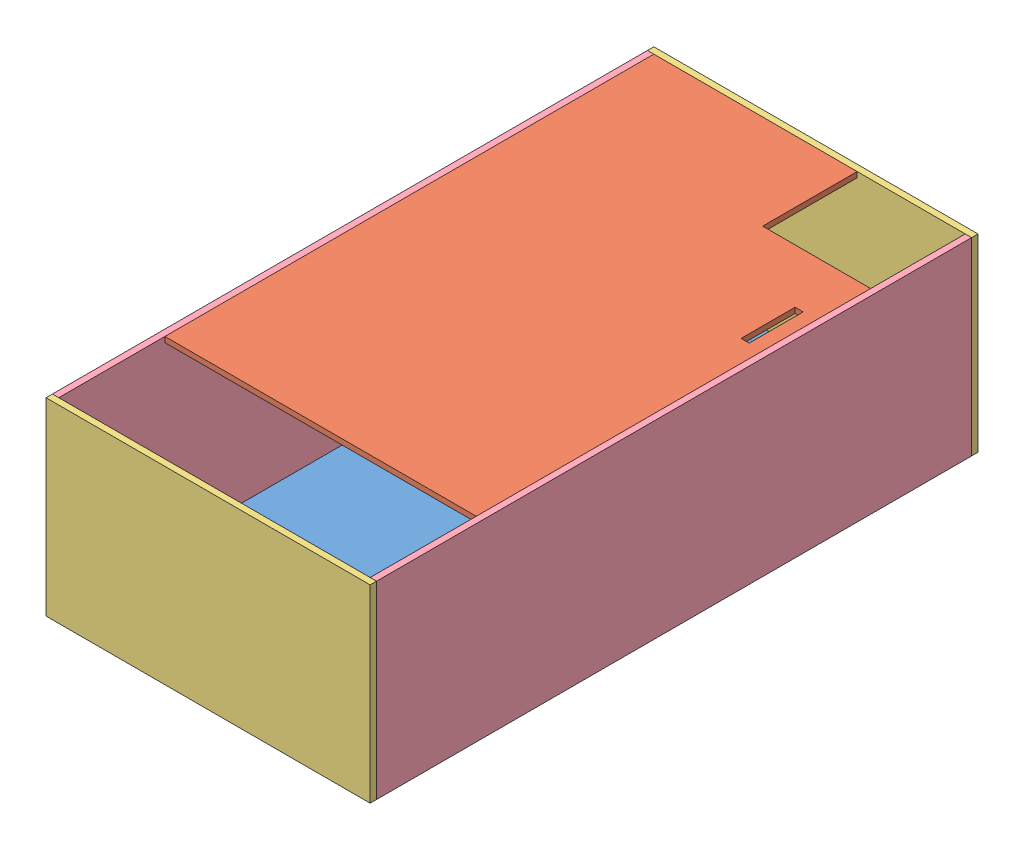
SolidWorks assembly pumpresovoir, configuration Default. Lengths in mm.
Overall size (152.4 88.9 285.75).
6 component instances, 4 part files, 13 mates.
Components (placement in the parent):
- waterbottom2-1: waterbottom2 [Default] at (-99.0826 -3.5009 -125.4041) size (146.41 3 279.76)
- top-1: top [Default] at (47.323 82.8591 -125.4041) x (0 0 1) z (-1 0 0) size (229.87 2.54 146.41)
- frontandback-1: frontandback [Default] at (-102.0798 85.3991 -128.4013) size (152.4 88.9 3)
- frontandback-2: frontandback [Default] at (-102.0798 85.3991 154.3515) size (152.4 88.9 3)
- prsides-1: prsides [Default] at (47.323 85.3991 154.3515) size (3 88.9 279.76)
- prsides-2: prsides [Default] at (-102.0798 85.3991 154.3515) size (3 88.9 279.76)
Mates (geometry in assembly coordinates):
- Coincident33: coincident anti-aligned: plane of top-1 through (122.6996 85.3991 -125.4041) normal (0 0 -1); plane of frontandback-1 through (-102.0798 85.3991 -125.4041) normal (0 0 1)
- Coincident34: coincident aligned: plane of waterbottom2-1 through (-99.0826 -3.5009 -125.4041) normal (0 -1 0); plane of frontandback-1 through (-102.0798 -3.5009 -125.4041) normal (0 -1 0)
- Coincident35: coincident anti-aligned: plane of waterbottom2-1 through (-99.0826 -0.5037 -125.4041) normal (0 0 -1); plane of frontandback-1 through (-102.0798 85.3991 -125.4041) normal (0 0 1)
- Coincident40: coincident anti-aligned: plane of frontandback-2 through (-102.0798 85.3991 154.3515) normal (0 0 -1); plane of prsides-1 through (50.3202 85.3991 154.3515) normal (0 0 1)
- Coincident41: coincident aligned: plane of frontandback-2 through (50.3202 85.3991 157.3487) normal (1 0 0); plane of prsides-1 through (50.3202 85.3991 154.3515) normal (1 0 0)
- Coincident42: coincident aligned: plane of frontandback-1 through (50.3202 85.3991 -125.4041) normal (1 0 0); plane of prsides-1 through (50.3202 85.3991 154.3515) normal (1 0 0)
- Coincident43: coincident anti-aligned: plane of frontandback-1 through (-102.0798 85.3991 -125.4041) normal (0 0 1); plane of prsides-1 through (50.3202 85.3991 -125.4041) normal (0 0 -1)
- Coincident46: coincident anti-aligned: plane of waterbottom2-1 through (47.323 -0.5037 -125.4041) normal (1 0 0); plane of prsides-1 through (47.323 85.3991 154.3515) normal (-1 0 0)
- Coincident47: coincident anti-aligned: plane of frontandback-1 through (-102.0798 85.3991 -125.4041) normal (0 0 1); plane of prsides-2 through (-99.0826 85.3991 -125.4041) normal (0 0 -1)
- Coincident48: coincident aligned: plane of frontandback-1 through (-102.0798 85.3991 -125.4041) normal (-1 0 0); plane of prsides-2 through (-102.0798 85.3991 154.3515) normal (-1 0 0)
- Coincident49: coincident aligned: plane of waterbottom2-1 through (-99.0826 -3.5009 -125.4041) normal (0 -1 0); plane of prsides-2 through (-99.0826 -3.5009 154.3515) normal (0 -1 0)
- Coincident50: coincident aligned: plane of top-1 through (47.323 85.3991 -125.4041) normal (0 1 0); plane of prsides-2 through (-99.0826 85.3991 154.3515) normal (0 1 0)
- Coincident51: coincident anti-aligned: plane of top-1 through (47.323 85.3991 -80.9541) normal (1 0 0); plane of prsides-1 through (47.323 85.3991 154.3515) normal (-1 0 0)
